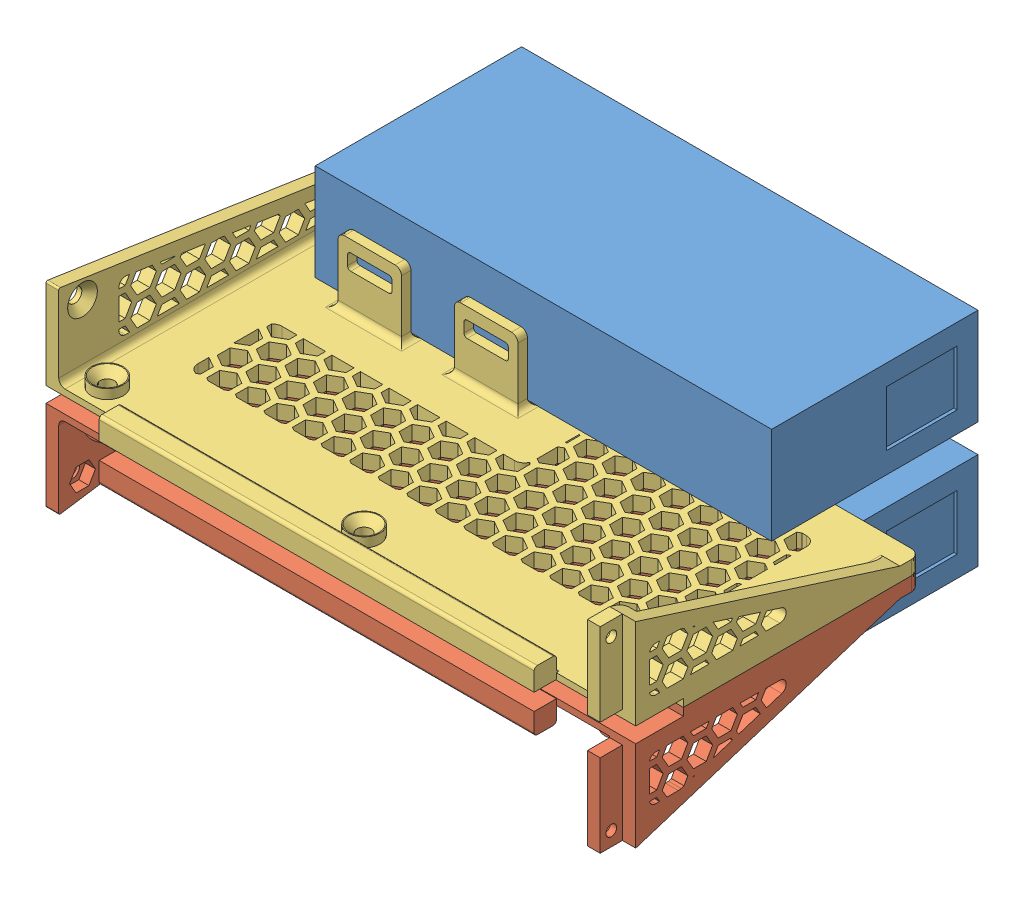
SolidWorks assembly test1, configuration Standard. Lengths in mm.
Overall size (185.75 69.9 146.92).
4 component instances, 3 part files, 9 mates.
Components (placement in the parent):
- Lenovo-135W-1: Lenovo-135W [Standard] at (54.9294 -0.4058 185.25) size (152.75 30.5 65)
- Left Extension-1: Left Extension [Standard] at (-48.7838 60.2542 158.8382) x (1 0 0) z (0 -1 0) size (185.75 146.92 30.9)
- Right Extension-1: Right Extension [Standard] at (-48.7838 8.8343 158.8382) x (1 0 0) z (0 -1 0) size (185.75 146.92 30.9)
- Lenovo-135W-2: Lenovo-135W [Standard] at (54.9294 38.9942 185.25) size (152.75 30.5 65)
Mates (geometry in assembly coordinates):
- Deckungsgleich1: coincident anti-aligned: plane of Lenovo-135W-1 through (54.9294 30.0942 185.25) normal (0 1 0); plane of Left Extension-1 through (-10.9456 30.0942 177.65) normal (0 -1 0)
- Deckungsgleich2: coincident anti-aligned: plane of Lenovo-135W-1 through (-88.8206 30.0942 185.25) normal (-1 0 0); plane of Left Extension-1 through (-88.8206 27.5942 141.75) normal (1 0 0)
- Breite1: width anti-aligned: plane of Left Extension-1 through (-77.154 9.5442 186.75) normal (0 0 -1); plane of Left Extension-1 through (-77.154 34.5442 118.75) normal (0 0 1); plane of Lenovo-135W-1 through (54.9294 30.0942 185.25) normal (0 0 1); plane of Lenovo-135W-1 through (54.9294 30.0942 120.25) normal (0 0 -1)
- Deckungsgleich6: coincident aligned: plane of Left Extension-1 through (-103.8206 32.3192 255.05) normal (0 0 1); plane of Right Extension-1 through (-103.8206 36.7692 255.05) normal (0 0 1)
- Deckungsgleich7: coincident anti-aligned: plane of Right Extension-1 through (-10.9456 38.9942 177.65) normal (0 1 0); plane of Lenovo-135W-2 through (54.9294 38.9942 185.25) normal (0 -1 0)
- Deckungsgleich8: coincident anti-aligned: plane of Right Extension-1 through (-88.8206 41.4942 141.75) normal (1 0 0); plane of Lenovo-135W-2 through (-88.8206 69.4942 185.25) normal (-1 0 0)
- Breite2: width anti-aligned: plane of Right Extension-1 through (-40.4873 34.5442 118.75) normal (0 0 1); plane of Right Extension-1 through (-20.4873 59.5442 186.75) normal (0 0 -1); plane of Lenovo-135W-2 through (54.9294 69.4942 120.25) normal (0 0 -1); plane of Lenovo-135W-2 through (54.9294 69.4942 185.25) normal (0 0 1)
- Deckungsgleich9: coincident anti-aligned: plane of Left Extension-1 through (-10.9456 34.5442 177.65) normal (0 1 0); plane of Right Extension-1 through (-10.9456 34.5442 177.65) normal (0 -1 0)
- Deckungsgleich10: coincident aligned: plane of Left Extension-1 through (81.9294 34.5442 240.05) normal (1 0 0); plane of Right Extension-1 through (81.9294 34.5442 240.05) normal (1 0 0)
